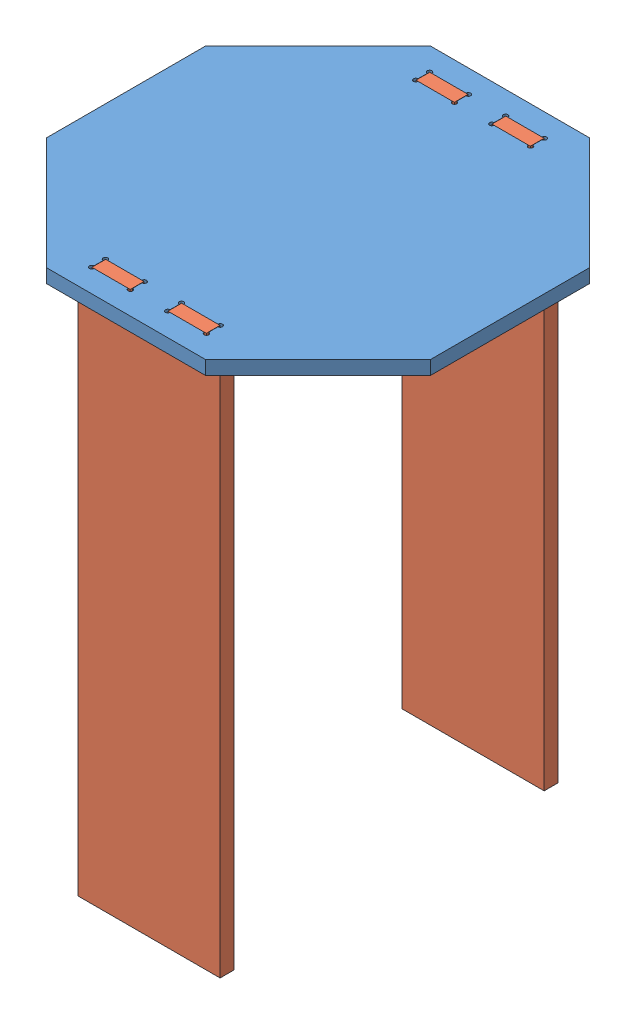
SolidWorks assembly Table_Assembly, configuration Default. Lengths in mm.
Overall size (500 718 500).
3 component instances, 2 part files, 0 mates.
Components (placement in the parent):
- Table_Top-1: Table_Top [Default] at (-74.0195 4.9518 29.5804) size (500 18 500)
- Part2-1: Part2 [Default] at (0 0.8658 -30) size (185 718 18)
- Part2-2: Part2 [Default] at (0 0.8658 -452) size (185 718 18)
